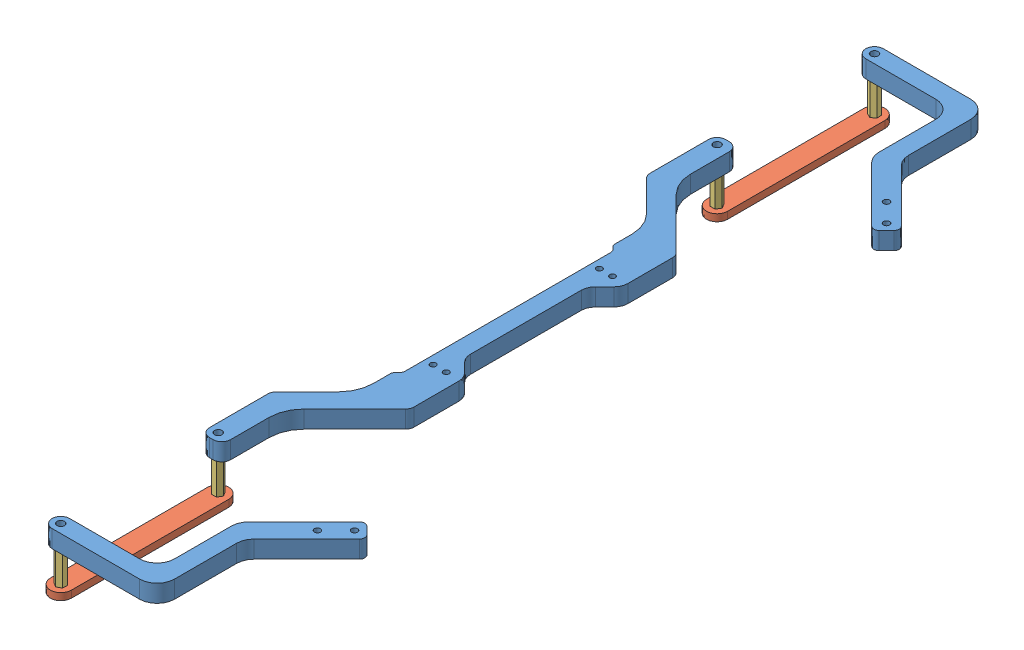
SolidWorks assembly ZB-抓板装配, configuration 默认. Lengths in mm.
Overall size (99.9 34 477.04).
7 component instances, 3 part files, 7 mates.
Components (placement in the parent):
- ZB2.0-抓板-1: ZB2.0-抓板 [默认] at (182.1906 -14.8454 435.0442) size (98.9 10 475.04)
- ZB20-抓板2-1: ZB20-抓板2 [默认] at (-43.0594 -35.8454 577.5662) x (0 0 1) z (0 1 0) size (102 12 4)
- zb-不锈钢柱M4x20-1: zb-不锈钢柱M4x20 [默认] at (-43.0594 -31.8454 577.5662) x (1 0 0) z (0 1 0) size (5.77 5 20)
- zb-不锈钢柱M4x20-2: zb-不锈钢柱M4x20 [默认] at (-43.0594 -31.8454 667.5662) x (0.062468 0 -0.998047) z (0 1 0) size (5.77 5 20)
- ZB20-抓板2-2: ZB20-抓板2 [默认] at (-43.0594 -31.8454 202.5221) x (0 0 1) z (0 -1 0) size (102 12 4)
- zb-不锈钢柱M4x20-3: zb-不锈钢柱M4x20 [默认] at (-43.0594 -11.8454 292.5221) x (1 0 0) z (0 -1 0) size (5.77 5 20)
- zb-不锈钢柱M4x20-4: zb-不锈钢柱M4x20 [默认] at (-43.0594 -11.8454 202.5221) x (0.062468 0 0.998047) z (0 -1 0) size (5.77 5 20)
Mates (geometry in assembly coordinates):
- 同心1: concentric anti-aligned: cylinder of ZB2.0-抓板-1 through (-43.0594 -11.8454 577.5662) axis (0 1 0) radius 2.15; cylinder of ZB-抓板2-1 through (-43.0594 -31.8454 577.5662) axis (0 -1 0) radius 2.15
- 同心3: concentric anti-aligned: circle of ZB-抓板-1; cylinder of 不锈钢柱M4x20-1 through (-43.0594 -11.8454 577.5662) axis (0 -1 0) radius 1.5
- 重合1: coincident anti-aligned: plane of ZB2.0-抓板-1 through (182.1906 -11.8454 435.0442) normal (0 -1 0); plane of 不锈钢柱M4x20-1 through (-43.0594 -11.8454 577.5662) normal (0 1 0)
- 重合2: coincident anti-aligned: plane of ZB-抓板2-1 through (-43.0594 -31.8454 577.5662) normal (0 1 0); plane of 不锈钢柱M4x20-1 through (-43.0594 -31.8454 577.5662) normal (0 -1 0)
- 重合4: coincident anti-aligned: plane of ZB-抓板2-1 through (-43.0594 -31.8454 577.5662) normal (0 1 0); plane of 不锈钢柱M4x20-2 through (-43.0594 -31.8454 667.5662) normal (0 -1 0)
- 同心5: concentric anti-aligned: cylinder of ZB2.0-抓板-1 through (-43.0594 -11.8454 667.5662) axis (0 1 0) radius 2.15; cylinder of zb-不锈钢柱M4x20-2 through (-43.0594 -11.8454 667.5662) axis (0 -1 0) radius 1.5
- 同心6: concentric aligned: cylinder of ZB20-抓板2-1 through (-43.0594 -31.8454 667.5662) axis (0 -1 0) radius 2.15; cylinder of zb-不锈钢柱M4x20-2 through (-43.0594 -11.8454 667.5662) axis (0 -1 0) radius 1.5
